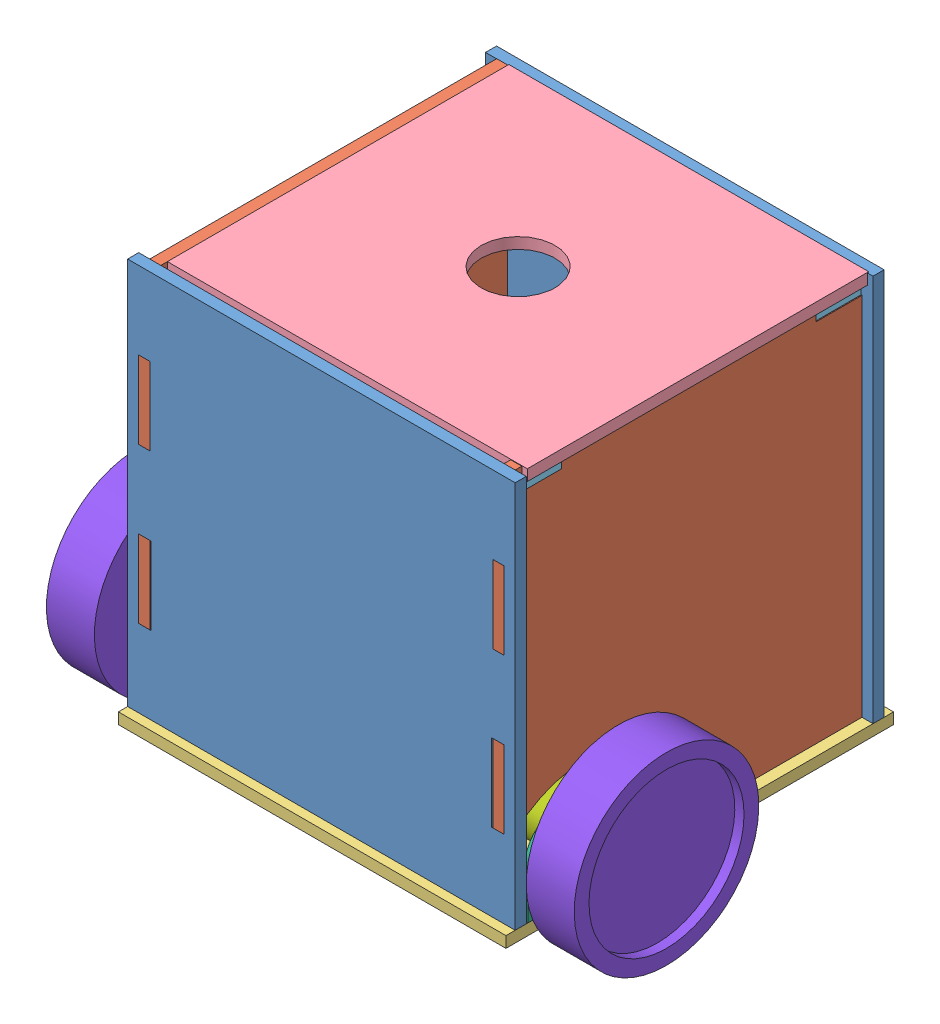
SolidWorks assembly Assem2, configuration Default. Lengths in mm.
Overall size (286 249.76 230.98).
16 component instances, 8 part files, 24 mates.
Components (placement in the parent):
- side back and front-1: side back and front [Default] at (-31.7093 67.9469 -11) x (-1 0 0) z (0 1 0) size (210 6 216)
- side squared-1: side squared [Default] at (50.8748 124.9286 -94.2857) x (0 0 1) z (0 -1 0) size (200 6 216)
- square base-1: square base [Default] at (-47.2743 0 -109.3835) size (210 6 210)
- top-1: top [Default] at (-34.1044 210.1559 -219.0747) x (0 0 -1) z (0.999999 0.001457 0) size (185 6 195)
- top holder-1: top holder [Default] at (-115.6035 204 21.0652) x (0 0 1) z (-1 0 0) size (24.5 6 198)
- top holder-2: top holder [Default] at (19.353 204.5004 -231.0652) x (0 0 -1) z (1 0 0) size (24.5 6 198)
- side squared-2: side squared [Default] at (-141.1252 124.9286 -94.2857) x (0 0 1) z (0 -1 0) size (200 6 216)
- side back and front-2: side back and front [Default] at (-31.7093 67.9469 -204.9084) x (-1 0 0) z (0 1 0) size (210 6 216)
- wheel_assy-1: wheel_assy [Default] at (-179.234 2.6183 8.7256) x (0 1 0) z (0 0 -1) size (139.95 113 139.95)
  - bracket-1: bracket [Default] at (33.8817 26.1088 57.7256) size (45 25 74)
  - emd30-1: emd30 [Default] at (26.622 101.1088 57.6925) x (-0.00456 0 0.99999) z (0.99999 0 0.00456) size (30 77 30)
  - wheel_to_check_hub_dimensions-1: wheel_to_check_hub_dimensions [Default] at (33.8817 14.1088 57.7256) x (0.598067 0 -0.801446) z (-0.801446 0 -0.598067) size (100 36 100)
- wheel_assy-2: wheel_assy [Default] at (82.9835 2.6183 -106.7256) x (0 1 0) z (0 0 1) size (139.95 113 139.95)
  - bracket-1: bracket [Default] at (33.8817 26.1088 57.7256) size (45 25 74)
  - emd30-1: emd30 [Default] at (26.622 101.1088 57.6925) x (-0.00456 0 0.99999) z (0.99999 0 0.00456) size (30 77 30)
  - wheel_to_check_hub_dimensions-1: wheel_to_check_hub_dimensions [Default] at (33.8817 14.1088 57.7256) x (0.598067 0 -0.801446) z (-0.801446 0 -0.598067) size (100 36 100)
Mates (geometry in assembly coordinates):
- Coincident6: coincident: line of side squared-1 through (44.8748 0 -162) axis (1 0 0); line of square base-1 through (44.3026 0 -162) axis (1 0 0)
- Coincident7: coincident: line of side squared-1 through (44.8748 0 -138) axis (0 0 1); line of square base-1 through (44.8748 0 -138) axis (0 0 1)
- Coincident12: coincident: plane of side squared-1 through (44.8748 210 -36) normal (0 0 1); plane of top holder-1 through (50.8748 210 -36) normal (0 0 -1)
- Coincident13: coincident: line of side squared-1 through (50.8748 204 -36) axis (0 1 0); line of top holder-1 through (50.8748 210 -36) axis (0 -1 0)
- Coincident15: coincident: plane of square base-1 through (-47.2743 0 -109.3835) normal (0 -1 0); plane of side squared-2 through (-147.1252 0 -162) normal (0 -1 0)
- Coincident16: coincident: plane of square base-1 through (-147.1252 6 -186) normal (0 0 1); plane of side squared-2 through (-147.1252 0 -186) normal (0 0 -1)
- Coincident17: coincident: plane of square base-1 through (-141.1252 6 -138) normal (-1 0 0); plane of side squared-2 through (-141.1252 6 -49) normal (1 0 0)
- Coincident18: coincident: plane of top holder-1 through (-115.6035 210 21.0652) normal (0 1 0); plane of side squared-2 through (-147.1252 210 -11) normal (0 -1 0)
- Coincident20: coincident: plane of square base-1 through (-47.2743 0 -109.3835) normal (0 -1 0); plane of assembly through (0 0 0) normal (0 1 0)
- Coincident21: coincident: plane of square base-1 through (-153.1252 6 0) normal (0 0 1); plane of assembly through (0 0 0) normal (0 0 1)
- Coincident22: coincident: line of side squared-1 through (50.8748 210 -174) axis (0 -1 0); line of top holder-2 through (50.8748 210.5004 -174) axis (0 -1 0)
- Coincident27: coincident: line of square base-1 through (-147.1252 6 -205) axis (0 0 1); line of side back and front-2 through (-147.1252 6 -198.9084) axis (0 0 -1)
- Coincident28: coincident: line of square base-1 through (50.8748 0 -199) axis (0 0 -1); line of side back and front-2 through (50.8748 0 -198.9084) axis (0 0 -1)
- Coincident35: coincident: line of top-1 through (-141.1252 216 -199.5625) axis (0 0 1); line of side squared-2 through (-141.1252 216 -11) axis (0 0 -1)
- Parallel4: parallel: line of side squared-1 through (44.8748 216 -11) axis (0 0 -1); line of top-1 through (53.8746 216.2841 -14.5625) axis (0 0 -1)
- Coincident38: coincident: line of side back and front-1 through (-147.1252 6 -5) axis (0 0 -1); line of square base-1 through (-147.1252 6 -11) axis (0 0 1)
- Coincident39: coincident: plane of side back and front-1 through (-31.7093 67.9469 -11) normal (0 0 -1); plane of square base-1 through (-147.1252 6 -11) normal (0 0 1)
- Coincident40: coincident: line of side back and front-1 through (50.8748 6 -5) axis (0 0 -1); line of square base-1 through (50.8748 6 -5) axis (0 0 -1)
- Coincident41: coincident: plane of square base-1 through (-47.2743 6 -109.3835) normal (0 1 0); plane of wheel_assy-1/bracket-1 through (-151.1252 6 -12) normal (0 -1 0)
- Coincident42: coincident: circle of square base-1; circle of wheel_assy-1/bracket-1
- Coincident43: coincident: circle of square base-1; circle of wheel_assy-1/bracket-1
- Coincident44: coincident: plane of square base-1 through (-47.2743 6 -109.3835) normal (0 1 0); plane of wheel_assy-2/bracket-1 through (54.8748 6 -86) normal (0 -1 0)
- Coincident45: coincident: circle of square base-1; circle of wheel_assy-2/bracket-1
- Coincident46: coincident: circle of square base-1; circle of wheel_assy-2/bracket-1
